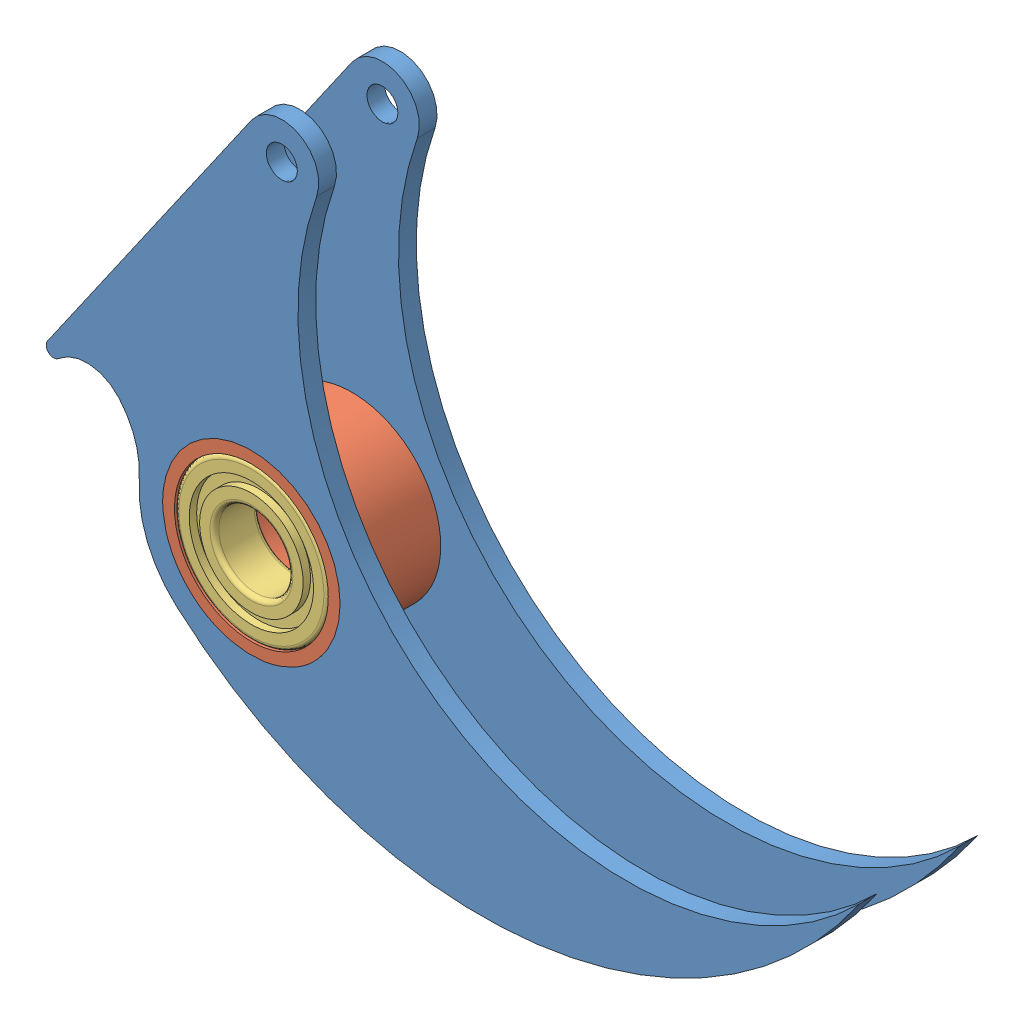
SolidWorks assembly ТП.016.03.01.00 - Рычаг подъема навески, configuration 00. Lengths in mm.
Overall size (274.94 199.54 40).
5 component instances, 3 part files, 9 mates.
Components (placement in the parent):
- ТП.016.03.01.01 - Зуб подъемника (6мм)-1: ТП.016.03.01.01 - Зуб подъемника (6мм) [--] at origin size (274.94 199.54 6)
- ТП.016.03.01.02 - Ступица подъема-1: ТП.016.03.01.02 - Ступица подъема [--] at (0 0 -20) x (0.995665 -0.093009 0) z (0 0 1) size (60 60 40)
- ТП.016.03.01.01 - Зуб подъемника (6мм)-2: ТП.016.03.01.01 - Зуб подъемника (6мм) [--] at (0 0 -34) size (274.94 199.54 6)
- Подшипник ГОСТ 8338-75 -1: Подшипник ГОСТ 8338-75  [Подшипник 205 ГОСТ 8338-75] at (0 0 -7.5) x (0 0 -1) z (0.763656 -0.645623 0) size (15 52 52)
- Подшипник ГОСТ 8338-75 -2: Подшипник ГОСТ 8338-75  [Подшипник 205 ГОСТ 8338-75] at (0 0 -32.5) x (0 0 -1) z (-0.53071 -0.847553 0) size (15 52 52)
Mates (geometry in assembly coordinates):
- Концентричный1: concentric: cylinder of ТП.016.03.01.01 - Зуб подъемника (6мм)-1 through (0 0 -6) axis (0 0 1) radius 30; cylinder of ТП.016.03.01.02 - Ступица подъема-1 through (0 0 980) axis (0 0 1) radius 30
- Совпадение1: coincident: plane of ТП.016.03.01.01 - Зуб подъемника (6мм)-1 through (77.648 87.5202 0) normal (0 0 1); plane of ТП.016.03.01.02 - Ступица подъема-1 through (2.7903 29.87 0) normal (0 0 1)
- Концентричный2: concentric: cylinder of ТП.016.03.01.02 - Ступица подъема-1 through (0 0 980) axis (0 0 1) radius 30; cylinder of ТП.016.03.01.01 - Зуб подъемника (6мм)-2 through (0 0 -40) axis (0 0 1) radius 30
- Совпадение2: coincident: plane of ТП.016.03.01.02 - Ступица подъема-1 through (2.7903 29.87 -40) normal (0 0 -1); plane of ТП.016.03.01.01 - Зуб подъемника (6мм)-2 through (77.648 87.5202 -40) normal (0 0 -1)
- Совпадение3: coincident: plane of ТП.016.03.01.01 - Зуб подъемника (6мм)-1 through (0.0334 126.6948 -6) normal (-0.820963 0.570982 0); plane of ТП.016.03.01.01 - Зуб подъемника (6мм)-2 through (0.0334 126.6948 -40) normal (-0.820963 0.570982 0)
- Концентричный3: concentric: cylinder of ТП.016.03.01.02 - Ступица подъема-1 through (0 0 -1020) axis (0 0 -1) radius 26; cylinder of Подшипник ГОСТ 8338-75 -1 through (0 0 992.5) axis (0 0 1) radius 26
- Совпадение4: coincident: plane of ТП.016.03.01.02 - Ступица подъема-1 through (2.7903 29.87 0) normal (0 0 1); plane of Подшипник ГОСТ 8338-75 -1 through (13.5581 16.0368 0) normal (0 0 1)
- Концентричный4: concentric: cylinder of ТП.016.03.01.02 - Ступица подъема-1 through (0 0 980) axis (0 0 1) radius 26; cylinder of Подшипник ГОСТ 8338-75 -2 through (0 0 967.5) axis (0 0 1) radius 26
- Совпадение5: coincident: plane of ТП.016.03.01.02 - Ступица подъема-1 through (2.7903 29.87 -40) normal (0 0 -1); plane of Подшипник ГОСТ 8338-75 -2 through (17.7986 -11.1449 -40) normal (0 0 -1)
